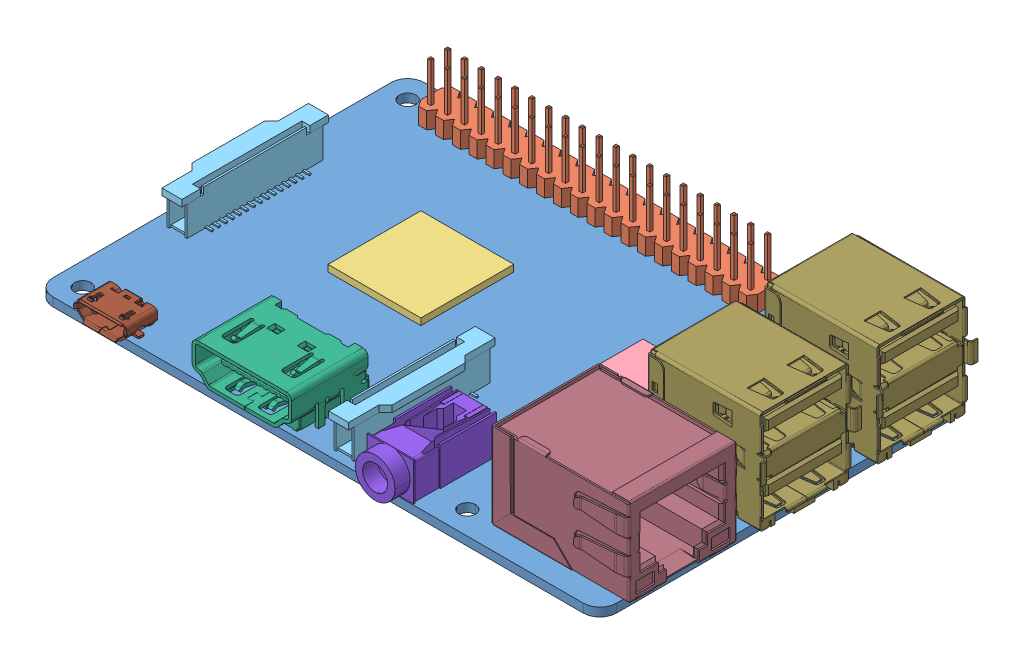
SolidWorks assembly RaspberryPi, configuration Default. Lengths in mm.
Overall size (89.62 18.75 58.3).
16 component instances, 13 part files, 0 mates.
Components (placement in the parent):
- RaspberryPi(2)^RaspberryPi-1: RaspberryPi(2)^RaspberryPi [Default] at origin size (89.62 18.75 58.3) (virtual)
  - Mainboard2^RaspberryPi(2)_RaspberryPi-1: Mainboard2^RaspberryPi(2)_RaspberryPi [Default] at origin size (85 1.3 56) (virtual)
  - GPIO^RaspberryPi(2)_RaspberryPi-1: GPIO^RaspberryPi(2)_RaspberryPi [Default] at (-11.37 0 -24.5) x (0 0 1) z (-1 0 0) size (5 11.5 50.8) (virtual)
  - Processor^RaspberryPi(2)_RaspberryPi-1: Processor^RaspberryPi(2)_RaspberryPi [Default] at (-15.5 0 -3) x (0 0 1) z (-1 0 0) size (14 1 14) (virtual)
  - GPU^RaspberryPi(2)_RaspberryPi-1: GPU^RaspberryPi(2)_RaspberryPi [Default] at (15.25 0 -5.75) x (0 0 1) z (-1 0 0) size (9.1 1 9.1) (virtual)
  - CameraAssembly^RaspberryPi(2)_RaspberryPi-1: CameraAssembly^RaspberryPi(2)_RaspberryPi [Default] at (10.0885 -2.9159 16.55) x (-1 0 0) z (0 0 -1) size (5.01 5.51 22.11) (virtual)
  - CameraAssembly^RaspberryPi(2)_RaspberryPi-2: CameraAssembly^RaspberryPi(2)_RaspberryPi [Default] at (-46.3885 -2.9159 0) size (5.01 5.51 22.11) (virtual)
  - HDMI^RaspberryPi(2)_RaspberryPi-1: HDMI^RaspberryPi(2)_RaspberryPi [Default] at (-10.2 0.27 29.3) size (15.04 8.38 12.15) (virtual)
  - RAM^RaspberryPi(2)_RaspberryPi-1: RAM^RaspberryPi(2)_RaspberryPi [Default] at (0.5 -2.3 -6) x (0 0 1) z (-1 0 0) size (12 1 12) (virtual)
  - Audio^RaspberryPi(2)_RaspberryPi-1: Audio^RaspberryPi(2)_RaspberryPi [Default] at (10.9 0.15 21.75) size (7 6 14.8) (virtual)
  - MicroSDSocket^RaspberryPi(2)_RaspberryPi-1: MicroSDSocket^RaspberryPi(2)_RaspberryPi [Default] at (-34.5 -1.3 -0.7) x (0 0 -1) z (-1 0 0) size (13 1.3 14) (virtual)
  - MicroSD^RaspberryPi(2)_RaspberryPi-1: MicroSD^RaspberryPi(2)_RaspberryPi [Default] at (-37 -2.3 0.1) x (0 0 1) z (-1 0 0) size (11.01 1 15) (virtual)
  - micro USB2^RaspberryPi(2)_RaspberryPi-1: micro USB2^RaspberryPi(2)_RaspberryPi [Default] at (-17.2704 -5.0969 44.9026) size (7.98 2.93 5.58) (virtual)
  - usb double^RaspberryPi(2)_RaspberryPi-1: usb double^RaspberryPi(2)_RaspberryPi [Default] at (30.38 -0.09 -18.85) x (0 0 -1) z (1 0 0) size (15.6 18.75 17.92) (virtual)
  - usb double^RaspberryPi(2)_RaspberryPi-2: usb double^RaspberryPi(2)_RaspberryPi [Default] at (30.38 -0.09 -1.25) x (0 0 -1) z (1 0 0) size (15.6 18.75 17.92) (virtual)
  - RJ45-LED^RaspberryPi(2)_RaspberryPi-1: RJ45-LED^RaspberryPi(2)_RaspberryPi [Default] at (34.11 7.4 17.348) x (1 0 0) z (0 -1 0) size (21.3 18 14.1) (virtual)
